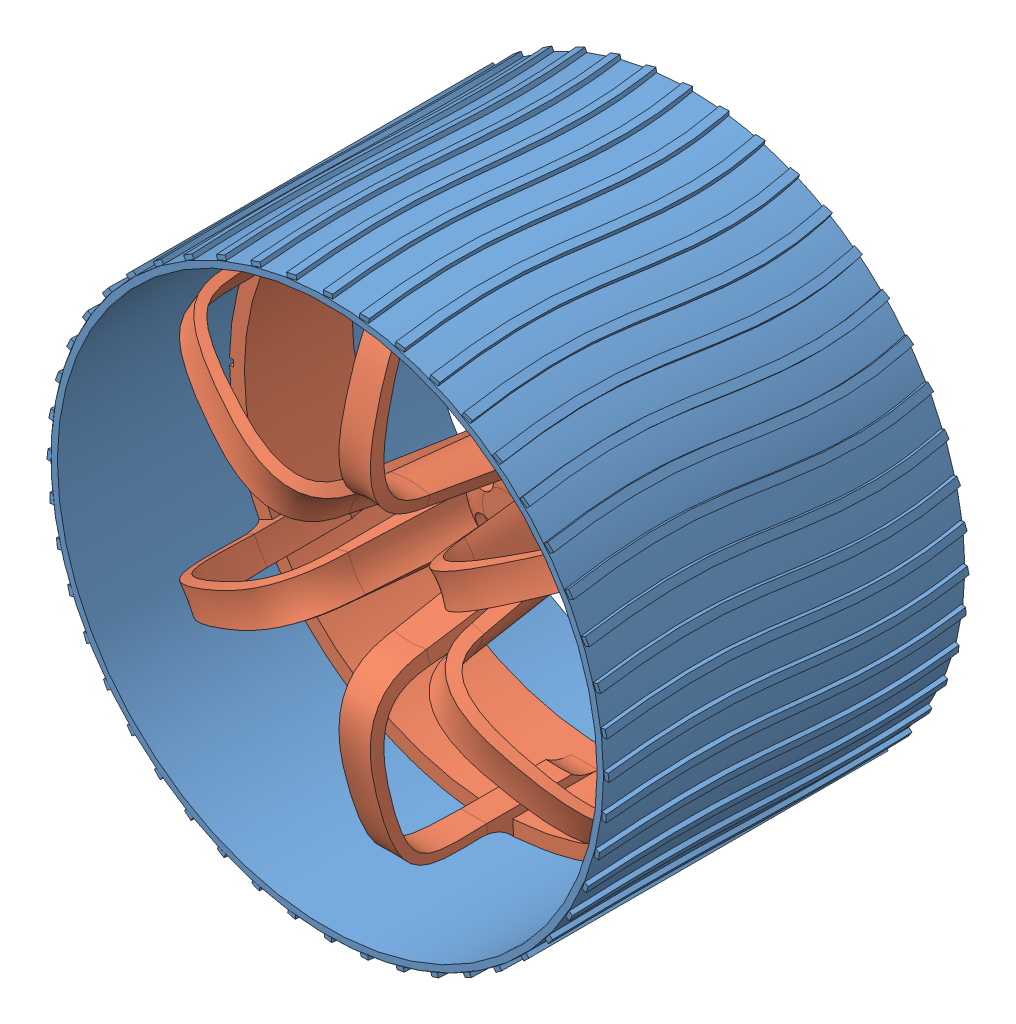
SolidWorks assembly Wheel, configuration Default. Lengths in mm.
Overall size (132 132 85).
2 component instances, 2 part files, 7 mates.
Components (placement in the parent):
- Wheel Part-1-1: Wheel Part-1 [Default] at origin size (132 132 85)
- Wheel Part-2-1: Wheel Part-2 [Default] at (0 0 -2) size (127 128.13 59.75)
Mates (geometry in assembly coordinates):
- Coincident1: coincident: plane of Wheel Part-1-1 through (99.4653 -0.75 -1) normal (0 0 -1); plane of Wheel Part-2-1 through (35.9653 0 -1) normal (0 0 1)
- Coincident2: coincident: plane of Wheel Part-1-1 through (99.4653 0.75 -1) normal (0 1 0); plane of Wheel Part-2-1 through (99.4653 0.75 -1) normal (0 -1 0)
- Coincident3: coincident: plane of Wheel Part-1-1 through (98.4653 0 0) normal (-1 0 0); plane of Wheel Part-2-1 through (98.4653 0.75 -1) normal (1 0 0)
- Lock1: lock: unknown of Wheel Part-1-1; unknown of Wheel Part-2-1
- Coincident4: coincident: plane of Wheel Part-1-1 through (0 0 0) normal (0 0 1); plane of assembly
- Coincident5: coincident: plane of Wheel Part-1-1 through (0 0 0) normal (0 1 0); plane of assembly
- Coincident6: coincident: plane of Wheel Part-1-1 through (0 0 0) normal (1 0 0); plane of assembly
